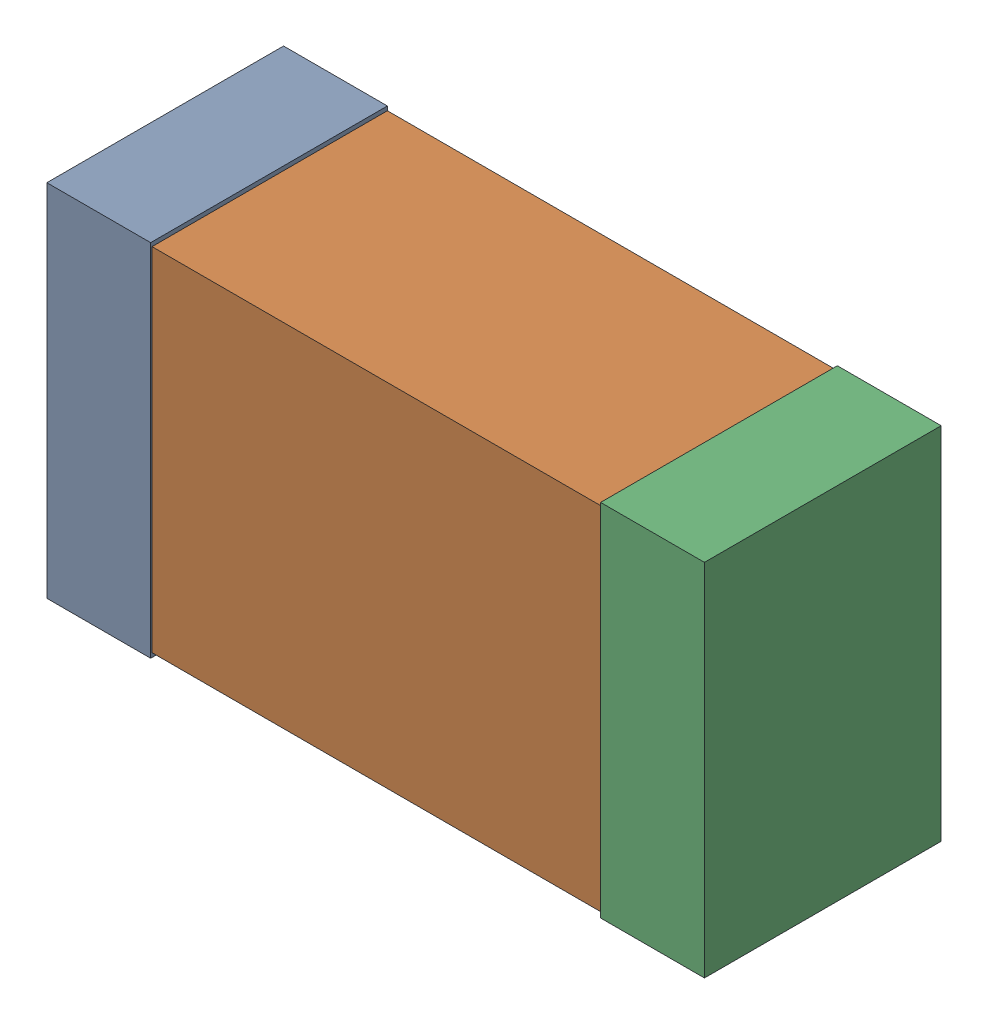
SolidWorks assembly R3_Motor_3Kanaloa_v2.0.0_Motor, configuration Default. Lengths in mm.
Overall size (2.38 1.3 0.85).
6 component instances, 2 part files, 0 mates.
Components (placement in the parent):
- 352877648-1: 352877648 [Default] at (41.867 92.964 0) size (0.38 1.3 0.85)
  - Extruded_14-1: Extruded_14 [Default] at origin size (0.38 1.3 0.85)
- 352877392-1: 352877392 [Default] at (42.867 92.964 0) size (2.2 1.27 0.85)
  - Extruded_15-1: Extruded_15 [Default] at origin size (2.2 1.27 0.85)
- 352877648-2: 352877648 [Default] at (43.867 92.964 0) size (0.38 1.3 0.85)
  - Extruded_14-1: Extruded_14 [Default] at origin size (0.38 1.3 0.85)
